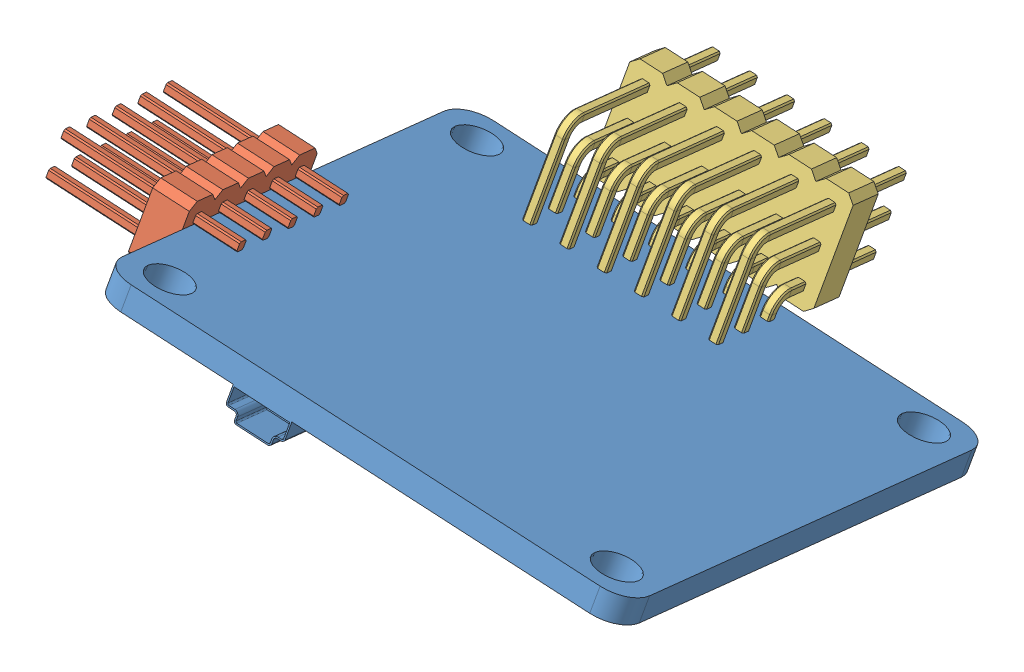
SolidWorks assembly Assem1, configuration Default. Lengths in mm.
Overall size (48.05 21.47 47.66).
3 component instances, 3 part files, 8 mates.
Components (placement in the parent):
- Distribution Board-1: Distribution Board [Default] at (4.8642 18.62 35.315) x (-0.971072 0.197152 0.134724) z (0.185524 0.26771 0.945469) size (36 3.75 36)
- Electrical unit-1: Electrical unit [Default] at (-10.2896 19.1715 36.6199) x (0.150335 0.943113 -0.296542) z (0.185524 0.26771 0.945469) size (5.08 12 12.7)
- Electrical unit2-1: Electrical unit2 [Default] at (6.2908 12.4593 25.145) x (-0.185524 -0.26771 -0.945469) z (0.971072 -0.197152 -0.134724) size (14.8 10.35 15.24)
Mates (geometry in assembly coordinates):
- Width2: width: plane of ? through (23.3331 19.5191 48.3592) normal (0.150335 0.943113 -0.296542); plane of ? through (23.07 17.8686 48.8781) normal (-0.150335 -0.943113 0.296542); plane of ? through (-19.7195 26.1766 47.4707) normal (-0.150335 -0.943113 0.296542); plane of ? through (-20.0036 24.3941 48.0312) normal (0.150335 0.943113 -0.296542)
- Coincident2: coincident: plane of ? through (-9.9464 24.5718 53.4587) normal (-0.971072 0.197152 0.134724); plane of ? through (-13.2395 19.5331 37.0963) normal (0.971072 -0.197152 -0.134724)
- Distance1: distance = 8 mm: plane of assembly; plane of assembly; plane of Distribution Board-1 through (-7.5966 24.9428 55.0079) normal (0.185524 0.26771 0.945469); plane of Electrical unit-1 through (-13.6257 22.5896 48.3959) normal (0.185524 0.26771 0.945469)
- Parallel1: parallel: plane of assembly; plane of assembly; plane of Distribution Board-1 through (25.0488 17.7042 48.5364) normal (0.971072 -0.197152 -0.134724); plane of Electrical unit2-1 through (6.1544 12.5781 14.5614) normal (0.971072 -0.197152 -0.134724)
- Parallel2: parallel: plane of assembly; plane of assembly; plane of Distribution Board-1 through (-14.2754 15.3053 20.971) normal (-0.185524 -0.26771 -0.945469); plane of Electrical unit2-1 through (4.4355 9.7822 15.6903) normal (-0.185524 -0.26771 -0.945469)
- Distance2: distance = 0.5 mm: plane of assembly; plane of assembly; plane of Electrical unit2-1 through (4.8993 10.4515 18.054) normal (0.185524 0.26771 0.945469); plane of Distribution Board-1 through (-14.2754 15.3053 20.971) normal (-0.185524 -0.26771 -0.945469)
- Distance3: distance = 8 mm: plane of assembly; plane of assembly; plane of Electrical unit2-1 through (-8.6448 15.5827 16.6146) normal (-0.971072 0.197152 0.134724); plane of Distribution Board-1 through (-9.9098 24.8017 53.3864) normal (-0.971072 0.197152 0.134724)
- Distance4: distance = 1.9 mm: plane of assembly; plane of assembly; plane of Distribution Board-1 through (23.1067 18.0985 48.8058) normal (-0.150335 -0.943113 0.296542); plane of Electrical unit2-1 through (5.5937 12.2051 14.777) normal (-0.150335 -0.943113 0.296542)
